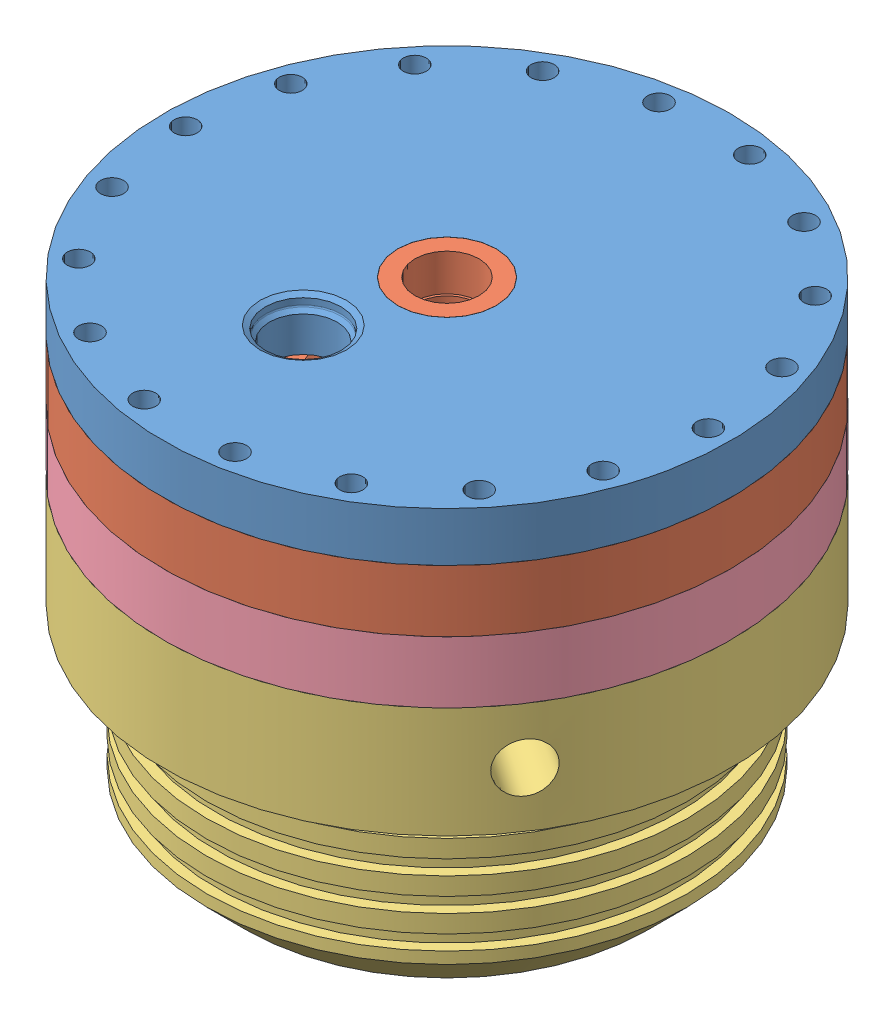
SolidWorks assembly Injector Assembly, configuration Default. Lengths in mm.
Overall size (206.55 115.94 206.55).
4 component instances, 4 part files, 10 mates.
Components (placement in the parent):
- Top Plate-1: Top Plate [Default] at (0 31.75 0) x (0.258819 0 -0.965926) z (0.965926 0 0.258819) size (146.05 12.7 146.05)
- InjectorV2-1: InjectorV2 [Default] x (0 0 -1) z (1 0 0) size (146.05 44.45 146.05)
- Flangea-2: Flangea [Default] at (0 -66.675 0) x (0.707107 0 -0.707107) z (0.707107 0 0.707107) size (146.05 71.49 146.05)
- Ring-1: Ring [Default] x (0.707107 0 -0.707107) z (0.707107 0 0.707107) size (146.05 15.88 146.05)
Mates (geometry in assembly coordinates):
- Coincident5: coincident anti-aligned: plane of Top Plate-1 through (0 31.75 0) normal (0 -1 0); plane of InjectorV2-1 through (0 31.75 0) normal (0 1 0)
- Concentric5: concentric anti-aligned: cylinder of InjectorV2-1 through (0 15.875 0) axis (0 1 0) radius 73.025; cylinder of Flangea-2 through (0 0 0) axis (0 -1 0) radius 73.025
- Concentric6: concentric aligned: cylinder of Flangea-2 through (0 0 0) axis (0 -1 0) radius 73.025; cylinder of Ring-1 through (0 15.875 0) axis (0 -1 0) radius 73.025
- Coincident6: coincident anti-aligned: plane of InjectorV2-1 through (0 15.875 0) normal (0 -1 0); plane of Ring-1 through (0 15.875 0) normal (0 1 0)
- Coincident7: coincident anti-aligned: plane of Flangea-2 through (0 0 0) normal (0 1 0); plane of Ring-1 through (0 0 0) normal (0 -1 0)
- Coincident8: coincident anti-aligned: plane of InjectorV2-1 through (0 0 0) normal (0 0 -1)
- Coincident9: coincident aligned: plane of InjectorV2-1 through (0 0 0) normal (0 1 0)
- Coincident12: coincident aligned: plane of InjectorV2-1 through (0 0 0) normal (1 0 0)
- Concentric9: concentric aligned: cylinder of Top Plate-1 through (0 44.45 0) axis (0 -1 0) radius 73.025; cylinder of Ring-1 through (0 15.875 0) axis (0 -1 0) radius 73.025
- Concentric10: concentric aligned: cylinder of Top Plate-1 through (11.6883 31.749 66.2874) axis (0 1 0) radius 2.9769; cylinder of InjectorV2-1 through (11.6883 0 66.2874) axis (0 1 0) radius 2.9769
